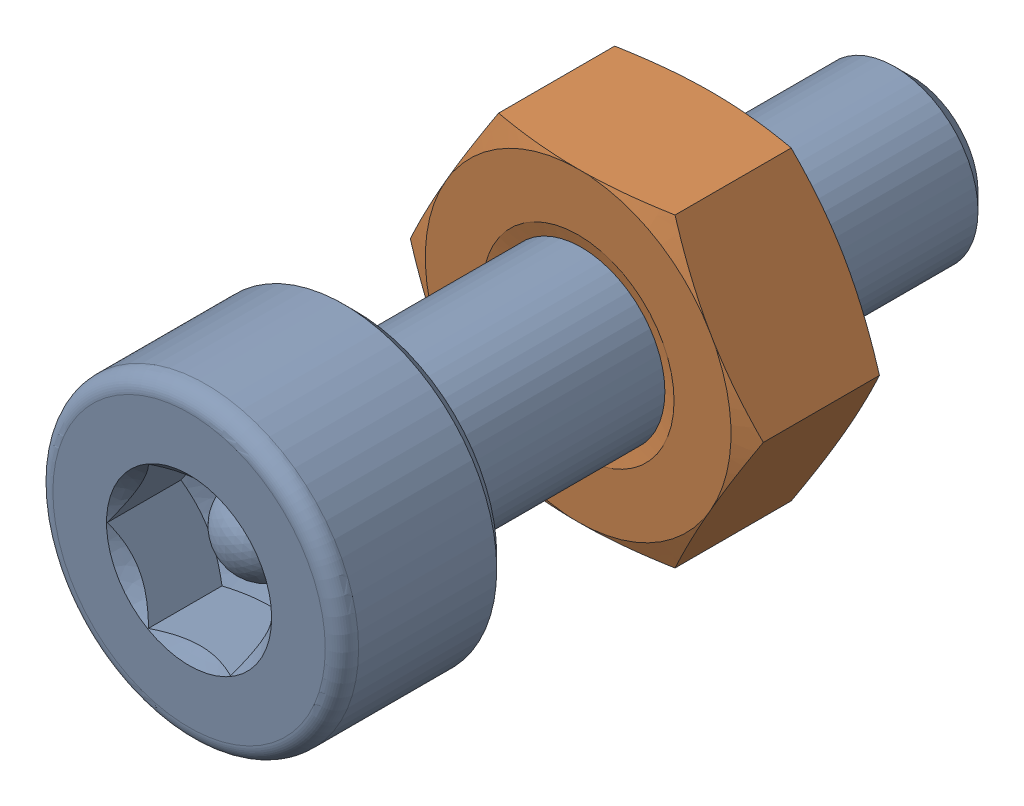
SolidWorks assembly Screw and Nut M3x010_012-1, configuration Varsayılan. Lengths in mm.
Overall size (6.35 5.5 13.14).
2 component instances, 2 part files, 0 mates.
Components (placement in the parent):
- M3x10-Screw011-1-1: M3x10-Screw011-1 [Varsayılan] at origin size (5.5 5.5 13.14)
- M3-Nut043-1-1: M3-Nut043-1 [Varsayılan] at (0 0 -4) x (-1 0 0) z (0 0 -1) size (6.35 5.5 2.4)
